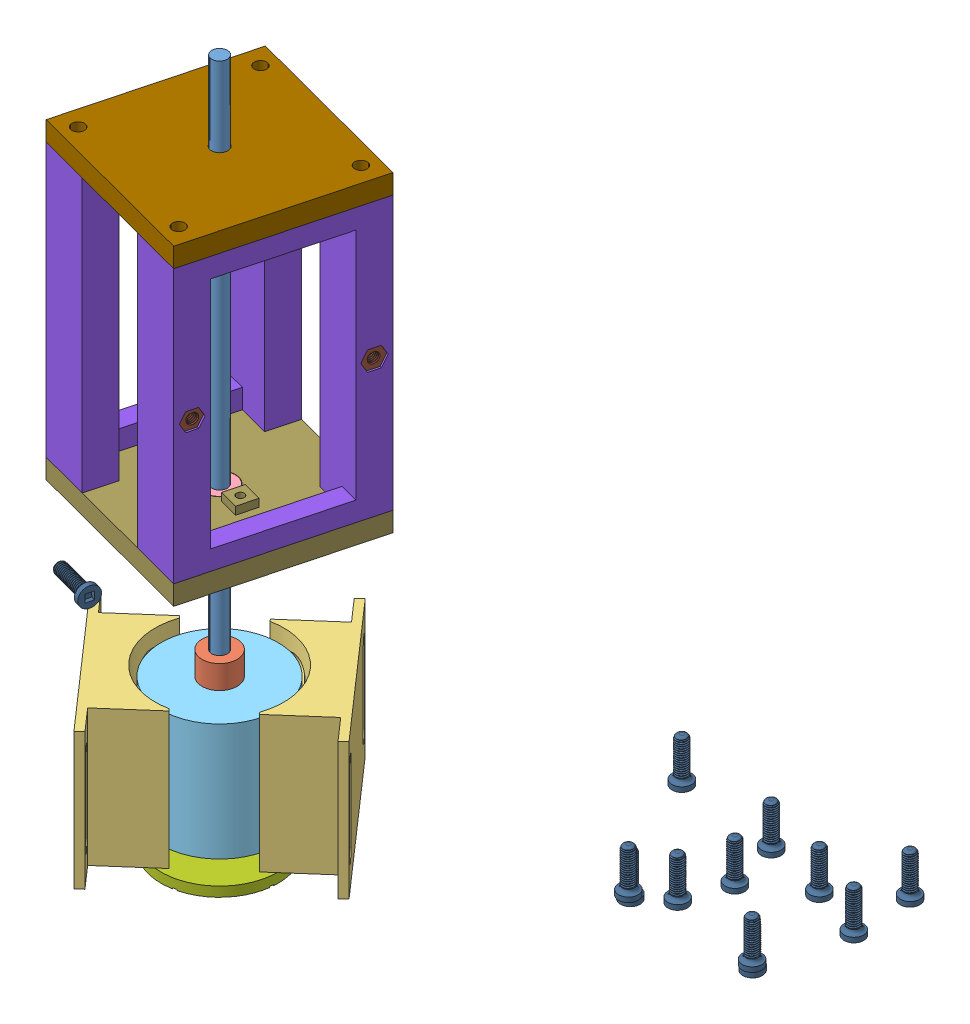
SolidWorks assembly motor 30mm diameter, configuration Default. Lengths in mm.
Overall size (286.31 208.16 173.67).
55 component instances, 12 part files, 103 mates.
Components (placement in the parent):
- 4mm diameter shaft 140mm long-1: 4mm diameter shaft 140mm long [Default] at (27.5327 12.6607 113.9865) size (4 140 4)
- collar-1: collar [Default] at (27.5327 14.5874 113.9865) x (0.999387 0 0.034997) z (-0.034997 0 0.999387) size (9 6 9.52)
- magnet_holder-1: magnet_holder [Default] at (57.6023 -0.4126 87.6082) x (0 1 0) z (0.659458 0 0.751741) size (35 16.75 45)
- collar-2: collar [Default] at (27.5327 -21.4126 113.9865) size (9 6 9.52)
- magnet_holder-2: magnet_holder [Default] at (-2.537 -0.4126 140.3648) x (0 1 0) z (-0.659458 0 -0.751741) size (35 16.75 45)
- shitty 4mm bearing-1: shitty 4mm bearing [Default] at (27.5327 130.3635 113.9865) x (-0.401704 0 -0.915769) z (-0.915769 0 0.401704) size (8 3 8)
- shitty 4mm bearing-2: shitty 4mm bearing [Default] at (27.5327 57.3635 113.9865) x (-0.401704 0 -0.915769) z (-0.915769 0 0.401704) size (8 3 8)
- rotor-like cylinder-1: rotor-like cylinder [Default] at (27.5327 -15.4126 113.9865) x (0.183673 0 0.982987) z (-0.982987 0 0.183673) size (30 30 30)
- 6.4mm magnet-1: 6.4mm magnet [Default] at (15.129 -0.4126 124.8676) x (0.659458 0 0.751741) z (-0.751741 0 0.659458) size (6.4 6.4 6.4)
- 6.4mm magnet-2: 6.4mm magnet [Default] at (22.8511 -10.4126 131.3958) x (0.659458 0 0.751741) z (-0.751741 0 0.659458) size (6.4 6.4 6.4)
- 6.4mm magnet-3: 6.4mm magnet [Default] at (9.662 9.5874 116.361) x (0.659458 0 0.751741) z (-0.751741 0 0.659458) size (6.4 6.4 6.4)
- 6.4mm magnet-4: 6.4mm magnet [Default] at (15.129 9.5874 124.8676) x (0.659458 0 0.751741) z (-0.751741 0 0.659458) size (6.4 6.4 6.4)
- 6.4mm magnet-5: 6.4mm magnet [Default] at (22.8511 9.5874 131.3958) x (0.659458 0 0.751741) z (-0.751741 0 0.659458) size (6.4 6.4 6.4)
- 6.4mm magnet-6: 6.4mm magnet [Default] at (22.8511 -0.4126 131.3958) x (0.659458 0 0.751741) z (-0.751741 0 0.659458) size (6.4 6.4 6.4)
- 6.4mm magnet-7: 6.4mm magnet [Default] at (15.129 -10.4126 124.8676) x (0.659458 0 0.751741) z (-0.751741 0 0.659458) size (6.4 6.4 6.4)
- 6.4mm magnet-8: 6.4mm magnet [Default] at (50.2145 9.5874 107.3915) x (0.659458 0 0.751741) z (-0.751741 0 0.659458) size (6.4 6.4 6.4)
- 6.4mm magnet-9: 6.4mm magnet [Default] at (50.2145 -0.4126 107.3915) x (0.659458 0 0.751741) z (-0.751741 0 0.659458) size (6.4 6.4 6.4)
- 6.4mm magnet-10: 6.4mm magnet [Default] at (9.662 -0.4126 116.361) x (0.659458 0 0.751741) z (-0.751741 0 0.659458) size (6.4 6.4 6.4)
- 6.4mm magnet-11: 6.4mm magnet [Default] at (44.7476 -0.4126 98.8849) x (0.659458 0 0.751741) z (-0.751741 0 0.659458) size (6.4 6.4 6.4)
- 6.4mm magnet-12: 6.4mm magnet [Default] at (44.7476 9.5874 98.8849) x (0.659458 0 0.751741) z (-0.751741 0 0.659458) size (6.4 6.4 6.4)
- 6.4mm magnet-13: 6.4mm magnet [Default] at (9.662 -10.4126 116.361) x (0.659458 0 0.751741) z (-0.751741 0 0.659458) size (6.4 6.4 6.4)
- 6.4mm magnet-14: 6.4mm magnet [Default] at (37.0254 -10.4126 92.3567) x (0.659458 0 0.751741) z (-0.751741 0 0.659458) size (6.4 6.4 6.4)
- 6.4mm magnet-15: 6.4mm magnet [Default] at (37.0254 -0.4126 92.3567) x (0.659458 0 0.751741) z (-0.751741 0 0.659458) size (6.4 6.4 6.4)
- 6.4mm magnet-16: 6.4mm magnet [Default] at (37.0254 9.5874 92.3567) x (0.659458 0 0.751741) z (-0.751741 0 0.659458) size (6.4 6.4 6.4)
- 6.4mm magnet-17: 6.4mm magnet [Default] at (44.7476 -10.4126 98.8849) x (0.659458 0 0.751741) z (-0.751741 0 0.659458) size (6.4 6.4 6.4)
- 6.4mm magnet-18: 6.4mm magnet [Default] at (50.2145 -10.4126 107.3915) x (0.659458 0 0.751741) z (-0.751741 0 0.659458) size (6.4 6.4 6.4)
- commutator-1: commutator [Default] at (27.5327 -23.9126 113.9865) x (0.977946 0 -0.20886) z (0.20886 0 0.977946) size (30 2.5 30)
- side-1: side [Default] at (44.9352 92.3635 118.5859) x (0 -1 0) z (-0.255519 0 0.966804) size (70 13 46)
- side-2: side [Default] at (10.1302 92.3635 109.3872) x (0 1 0) z (-0.255519 0 0.966804) size (70 13 46)
- top plate-1: top plate [Default] at (27.5327 127.3635 113.9865) x (0.966804 0 0.255519) z (-0.255519 0 0.966804) size (46 5 46)
- m3 10mm screw-1: m3 10mm screw [Default] at (40.4259 62.9575 161.0858) x (-0.006958 0.999629 0.026326) z (-0.255424 -0.02723 0.966446) size (5 11.25 5)
- threaded insert m3-1: threaded insert m3 [Default] at (49.9428 57.8635 100.1277) x (0.966804 0 0.255519) z (-0.255519 0 0.966804) size (5.77 8.2 5)
- bottom plate-1: bottom plate [Default] at (27.5327 57.3635 113.9865) x (-0.966804 0 -0.255519) z (-0.255519 0 0.966804) size (46 7 46)
- threaded insert m3-2: threaded insert m3 [Default] at (14.8962 126.8635 90.8651) x (-0.966804 0 -0.255519) z (-0.255519 0 0.966804) size (5.77 8.2 5)
- m3 10mm screw-2: m3 10mm screw [Default] at (257.6758 112.3701 207.42) size (5 11.25 5)
- threaded insert m3-3: threaded insert m3 [Default] at (5.1226 126.8635 127.8454) x (-0.966804 0 -0.255519) z (-0.255519 0 0.966804) size (5.77 8.2 5)
- m3 10mm screw-3: m3 10mm screw [Default] at (271.6653 150.9954 240.6279) size (5 11.25 5)
- threaded insert m3-4: threaded insert m3 [Default] at (40.1692 118.8635 137.1079) x (0.966804 0 0.255519) z (-0.255519 0 0.966804) size (5.77 8.2 5)
- m3 10mm screw-4: m3 10mm screw [Default] at (275.8721 126.0941 185.2162) size (5 11.25 5)
- threaded insert m3-5: threaded insert m3 [Default] at (0.9642 92.5248 126.4574) x (0.127759 -0.866025 -0.483402) z (-0.221286 -0.5 0.837277) size (5.77 8.2 5)
- m3 10mm screw-5: m3 10mm screw [Default] at (266.8499 122.8272 216.7168) size (5 11.25 5)
- threaded insert m3-6: threaded insert m3 [Default] at (10.6664 92.3635 89.7472) x (0.127759 -0.866025 -0.483402) z (-0.221286 -0.5 0.837277) size (5.77 8.2 5)
- m3 10mm screw-6: m3 10mm screw [Default] at (277.7139 156.6598 222.6465) size (5 11.25 5)
- threaded insert m3-7: threaded insert m3 [Default] at (40.1692 57.8635 137.1079) x (0.966804 0 0.255519) z (-0.255519 0 0.966804) size (5.77 8.2 5)
- m3 10mm screw-7: m3 10mm screw [Default] at (271.2692 134.1604 203.8679) size (5 11.25 5)
- threaded insert m3-8: threaded insert m3 [Default] at (46.4381 92.3635 99.2014) x (0.127759 -0.866025 -0.483402) z (-0.221286 -0.5 0.837277) size (5.77 8.2 5)
- m3 10mm screw-8: m3 10mm screw [Default] at (273.3226 122.8159 197.0775) size (5 11.25 5)
- threaded insert m3-9: threaded insert m3 [Default] at (5.1226 57.8635 127.8454) x (0.966804 0 0.255519) z (-0.255519 0 0.966804) size (5.77 8.2 5)
- m3 10mm screw-9: m3 10mm screw [Default] at (266.4595 142.05 220.7177) size (5 11.25 5)
- threaded insert m3-10: threaded insert m3 [Default] at (14.8962 65.8635 90.8651) x (-0.966804 0 -0.255519) z (-0.255519 0 0.966804) size (5.77 8.2 5)
- m3 10mm screw-10: m3 10mm screw [Default] at (270.1636 157.5042 251.7523) size (5 11.25 5)
- threaded insert m3-11: threaded insert m3 [Default] at (49.9428 126.8635 100.1277) x (-0.966804 0 -0.255519) z (-0.255519 0 0.966804) size (5.77 8.2 5)
- m3 10mm screw-11: m3 10mm screw [Default] at (269.274 174.2452 237.1528) size (5 11.25 5)
- threaded insert m3-12: threaded insert m3 [Default] at (36.7121 92.3635 136.0016) x (0.127759 -0.866025 -0.483402) z (-0.221286 -0.5 0.837277) size (5.77 8.2 5)
- m3 10mm screw-12: m3 10mm screw [Default] at (255.8389 142.0395 236.9166) size (5 11.25 5)
Mates (geometry in assembly coordinates):
- Concentric1: concentric aligned: circle of 4mm diameter shaft 140mm long-1; circle of rotor-like cylinder-1
- Concentric2: concentric aligned: circle of collar-1; circle of rotor-like cylinder-1
- Coincident6: coincident anti-aligned: plane of collar-1 through (27.5327 14.5874 113.9865) normal (0 -1 0); plane of rotor-like cylinder-1 through (27.5327 14.5874 113.9865) normal (0 1 0)
- Concentric4: concentric aligned: circle of 4mm diameter shaft 140mm long-1; circle of collar-2
- Coincident8: coincident anti-aligned: plane of collar-2 through (27.5327 -15.4126 113.9865) normal (0 1 0); plane of rotor-like cylinder-1 through (27.5327 -15.4126 113.9865) normal (0 -1 0)
- Concentric5: concentric anti-aligned: cylinder of magnet_holder-1 through (27.5327 -17.9126 113.9865) axis (0 1 0) radius 16.5; cylinder of rotor-like cylinder-1 through (27.5327 14.5874 113.9865) axis (0 -1 0) radius 15
- Concentric6: concentric anti-aligned: cylinder of magnet_holder-2 through (27.5327 -17.9126 113.9865) axis (0 1 0) radius 16.5; cylinder of rotor-like cylinder-1 through (27.5327 14.5874 113.9865) axis (0 -1 0) radius 15
- Parallel1: parallel aligned: plane of magnet_holder-1 through (7.3549 -17.9126 151.641) normal (0.659458 0 0.751741); plane of magnet_holder-2 through (67.4942 -17.9126 98.8843) normal (0.659458 0 0.751741)
- Coincident11: coincident aligned: plane of magnet_holder-1 through (7.3549 17.0874 151.641) normal (0 1 0); plane of magnet_holder-2 through (47.7105 17.0874 76.3321) normal (0 1 0)
- Concentric7: concentric anti-aligned: circle of magnet_holder-2; circle of 6.4mm magnet-5
- Coincident14: coincident anti-aligned: plane of magnet_holder-2 through (18.04 9.5874 135.6163) normal (0.751741 0 -0.659458); plane of 6.4mm magnet-5 through (18.04 9.5874 135.6163) normal (-0.751741 0 0.659458)
- Concentric8: concentric anti-aligned: circle of magnet_holder-2; circle of 6.4mm magnet-4
- Coincident16: coincident anti-aligned: plane of magnet_holder-2 through (10.3178 9.5874 129.0881) normal (0.751741 0 -0.659458); plane of 6.4mm magnet-4 through (10.3178 9.5874 129.0881) normal (-0.751741 0 0.659458)
- Concentric9: concentric anti-aligned: circle of magnet_holder-2; circle of 6.4mm magnet-3
- Coincident18: coincident anti-aligned: plane of magnet_holder-2 through (4.8508 9.5874 120.5815) normal (0.751741 0 -0.659458); plane of 6.4mm magnet-3 through (4.8508 9.5874 120.5815) normal (-0.751741 0 0.659458)
- Concentric10: concentric anti-aligned: circle of magnet_holder-2; circle of 6.4mm magnet-6
- Coincident19: coincident anti-aligned: plane of magnet_holder-2 through (18.04 -0.4126 135.6163) normal (0.751741 0 -0.659458); plane of 6.4mm magnet-6 through (18.04 -0.4126 135.6163) normal (-0.751741 0 0.659458)
- Concentric11: concentric anti-aligned: circle of magnet_holder-2; circle of 6.4mm magnet-2
- Coincident21: coincident anti-aligned: plane of magnet_holder-2 through (18.04 -10.4126 135.6163) normal (0.751741 0 -0.659458); plane of 6.4mm magnet-2 through (18.04 -10.4126 135.6163) normal (-0.751741 0 0.659458)
- Concentric12: concentric anti-aligned: circle of magnet_holder-2; circle of 6.4mm magnet-1
- Coincident23: coincident anti-aligned: plane of magnet_holder-2 through (10.3178 -0.4126 129.0881) normal (0.751741 0 -0.659458); plane of 6.4mm magnet-1 through (10.3178 -0.4126 129.0881) normal (-0.751741 0 0.659458)
- Concentric13: concentric anti-aligned: circle of magnet_holder-2; circle of 6.4mm magnet-7
- Coincident25: coincident anti-aligned: plane of magnet_holder-2 through (10.3178 -10.4126 129.0881) normal (0.751741 0 -0.659458); plane of 6.4mm magnet-7 through (10.3178 -10.4126 129.0881) normal (-0.751741 0 0.659458)
- Concentric14: concentric anti-aligned: circle of magnet_holder-2; circle of 6.4mm magnet-13
- Coincident27: coincident anti-aligned: plane of magnet_holder-2 through (4.8508 -10.4126 120.5815) normal (0.751741 0 -0.659458); plane of 6.4mm magnet-13 through (4.8508 -10.4126 120.5815) normal (-0.751741 0 0.659458)
- Concentric15: concentric anti-aligned: circle of magnet_holder-2; circle of 6.4mm magnet-10
- Coincident28: coincident anti-aligned: plane of magnet_holder-2 through (4.8508 -0.4126 120.5815) normal (0.751741 0 -0.659458); plane of 6.4mm magnet-10 through (4.8508 -0.4126 120.5815) normal (-0.751741 0 0.659458)
- Concentric16: concentric aligned: circle of magnet_holder-1; circle of 6.4mm magnet-8
- Concentric21: concentric aligned: circle of magnet_holder-1; circle of 6.4mm magnet-9
- Concentric22: concentric aligned: circle of magnet_holder-1; circle of 6.4mm magnet-18
- Concentric23: concentric aligned: circle of magnet_holder-1; circle of 6.4mm magnet-12
- Concentric24: concentric aligned: circle of magnet_holder-1; circle of 6.4mm magnet-11
- Concentric25: concentric aligned: circle of magnet_holder-1; circle of 6.4mm magnet-17
- Concentric26: concentric aligned: circle of magnet_holder-1; circle of 6.4mm magnet-14
- Concentric27: concentric aligned: circle of magnet_holder-1; circle of 6.4mm magnet-15
- Concentric28: concentric aligned: circle of magnet_holder-1; circle of 6.4mm magnet-16
- Coincident39: coincident anti-aligned: plane of magnet_holder-1 through (50.2145 9.5874 107.3915) normal (-0.751741 0 0.659458); plane of 6.4mm magnet-8 through (50.2145 9.5874 107.3915) normal (0.751741 0 -0.659458)
- Coincident40: coincident anti-aligned: plane of magnet_holder-1 through (44.7476 9.5874 98.8849) normal (-0.751741 0 0.659458); plane of 6.4mm magnet-12 through (44.7476 9.5874 98.8849) normal (0.751741 0 -0.659458)
- Coincident41: coincident anti-aligned: plane of magnet_holder-1 through (37.0254 9.5874 92.3567) normal (-0.751741 0 0.659458); plane of 6.4mm magnet-16 through (37.0254 9.5874 92.3567) normal (0.751741 0 -0.659458)
- Coincident42: coincident anti-aligned: plane of magnet_holder-1 through (37.0254 -0.4126 92.3567) normal (-0.751741 0 0.659458); plane of 6.4mm magnet-15 through (37.0254 -0.4126 92.3567) normal (0.751741 0 -0.659458)
- Coincident43: coincident anti-aligned: plane of magnet_holder-1 through (44.7476 -0.4126 98.8849) normal (-0.751741 0 0.659458); plane of 6.4mm magnet-11 through (44.7476 -0.4126 98.8849) normal (0.751741 0 -0.659458)
- Coincident44: coincident anti-aligned: plane of magnet_holder-1 through (50.2145 -0.4126 107.3915) normal (-0.751741 0 0.659458); plane of 6.4mm magnet-9 through (50.2145 -0.4126 107.3915) normal (0.751741 0 -0.659458)
- Coincident45: coincident anti-aligned: plane of magnet_holder-1 through (50.2145 -10.4126 107.3915) normal (-0.751741 0 0.659458); plane of 6.4mm magnet-18 through (50.2145 -10.4126 107.3915) normal (0.751741 0 -0.659458)
- Coincident46: coincident anti-aligned: plane of magnet_holder-1 through (44.7476 -10.4126 98.8849) normal (-0.751741 0 0.659458); plane of 6.4mm magnet-17 through (44.7476 -10.4126 98.8849) normal (0.751741 0 -0.659458)
- Coincident47: coincident anti-aligned: plane of magnet_holder-1 through (37.0254 -10.4126 92.3567) normal (-0.751741 0 0.659458); plane of 6.4mm magnet-14 through (37.0254 -10.4126 92.3567) normal (0.751741 0 -0.659458)
- Distance1: distance = 2.5 mm aligned: plane of magnet_holder-2 through (47.7105 -17.9126 76.3321) normal (0 -1 0); plane of rotor-like cylinder-1 through (27.5327 -15.4126 113.9865) normal (0 -1 0)
- Concentric29: concentric anti-aligned: circle of collar-2; cylinder of commutator-1 through (27.5327 -21.4126 113.9865) axis (0 -1 0) radius 2
- Coincident49: coincident anti-aligned: plane of collar-2 through (27.5327 -21.4126 113.9865) normal (0 -1 0); plane of commutator-1 through (27.5327 -21.4126 113.9865) normal (0 1 0)
- Coincident51: coincident anti-aligned: plane of side-1 through (44.9352 118.8635 118.5859) normal (0 1 0); plane of threaded insert m3-4 through (40.1692 118.8635 137.1079) normal (0 -1 0)
- Coincident52: coincident aligned: line of side-1 through (38.135 118.8635 139.1561) axis (0.966804 0 0.255519); line of threaded insert m3-4 through (38.135 118.8635 139.1561) axis (0.966804 0 0.255519)
- Coincident53: coincident aligned: line of side-1 through (37.3783 118.8635 136.3703) axis (0.262116 0 0.965036); line of threaded insert m3-4 through (37.3783 118.8635 136.3703) axis (0.262116 0 0.965036)
- Coincident54: coincident anti-aligned: plane of side-1 through (44.9352 118.8635 118.5859) normal (0 1 0); plane of threaded insert m3-11 through (49.9428 118.8635 100.1277) normal (0 -1 0)
- Coincident55: coincident anti-aligned: line of side-1 through (49.1861 118.8635 97.3418) axis (-0.704688 0 0.709518); line of threaded insert m3-11 through (47.1519 118.8635 99.39) axis (0.704688 0 -0.709518)
- Coincident56: coincident anti-aligned: line of side-1 through (50.6995 118.8635 102.9135) axis (0.704688 0 -0.709518); line of threaded insert m3-11 through (52.7337 118.8635 100.8653) axis (-0.704688 0 0.709518)
- Coincident57: coincident anti-aligned: line of side-1 through (47.9085 118.8635 102.1759) axis (0.966804 0 0.255519); line of threaded insert m3-11 through (50.6995 118.8635 102.9135) axis (-0.966804 0 -0.255519)
- Coincident65: coincident anti-aligned: plane of side-1 through (41.5513 92.3635 117.6915) normal (0.966804 0 0.255519); plane of threaded insert m3-8 through (46.4381 92.3635 99.2014) normal (-0.966804 0 -0.255519)
- Coincident66: coincident aligned: line of side-1 through (46.0693 94.8635 100.5969) axis (-0.127759 -0.866025 0.483402); line of threaded insert m3-8 through (46.0693 94.8635 100.5969) axis (-0.127759 -0.866025 0.483402)
- Coincident67: coincident aligned: line of side-1 through (45.7005 92.3635 101.9923) axis (0.127759 -0.866025 -0.483402); line of threaded insert m3-8 through (45.7005 92.3635 101.9923) axis (0.127759 -0.866025 -0.483402)
- Coincident68: coincident anti-aligned: plane of side-1 through (41.5513 92.3635 117.6915) normal (0.966804 0 0.255519); plane of threaded insert m3-12 through (36.7121 92.3635 136.0016) normal (-0.966804 0 -0.255519)
- Coincident69: coincident aligned: line of side-1 through (36.3195 94.7022 137.4871) axis (-0.127759 -0.866025 0.483402); line of threaded insert m3-12 through (36.3433 94.8635 137.3971) axis (-0.127759 -0.866025 0.483402)
- Coincident70: coincident aligned: line of side-1 through (35.9745 92.3635 138.7925) axis (0.127759 -0.866025 -0.483402); line of threaded insert m3-12 through (35.9745 92.3635 138.7925) axis (0.127759 -0.866025 -0.483402)
- Coincident71: coincident anti-aligned: plane of side-1 through (44.9352 65.8635 118.5859) normal (0 -1 0); plane of threaded insert m3-7 through (40.1692 65.8635 137.1079) normal (0 1 0)
- Coincident72: coincident anti-aligned: line of side-1 through (39.4125 65.8635 134.3221) axis (0.966804 0 0.255519); line of threaded insert m3-7 through (42.2035 65.8635 135.0597) axis (-0.966804 0 -0.255519)
- Coincident73: coincident anti-aligned: line of side-1 through (38.135 65.8635 139.1561) axis (-0.262116 0 -0.965036); line of threaded insert m3-7 through (37.3783 65.8635 136.3703) axis (0.262116 0 0.965036)
- Coincident74: coincident anti-aligned: plane of side-1 through (44.9352 65.8635 118.5859) normal (0 -1 0); plane of threaded insert m3-1 through (49.9428 65.8635 100.1277) normal (0 1 0)
- Coincident75: coincident: plane of side-1 through (51.9771 65.8635 98.0795) normal (-0.965036 0 0.262116); line of threaded insert m3-1 through (52.7337 65.8635 100.8653) axis (-0.262116 0 -0.965036)
- Coincident76: coincident anti-aligned: plane of side-1 through (52.7337 65.8635 100.8653) normal (-0.709518 0 -0.704688); plane of threaded insert m3-1 through (50.6995 65.8635 102.9135) normal (0.709518 0 0.704688)
- Coincident77: coincident anti-aligned: plane of side-2 through (10.1302 118.8635 109.3872) normal (0 1 0); plane of threaded insert m3-3 through (5.1226 118.8635 127.8454) normal (0 -1 0)
- Coincident78: coincident anti-aligned: plane of side-2 through (7.1568 118.8635 125.7972) normal (-0.255519 0 0.966804); plane of threaded insert m3-3 through (4.3659 118.8635 125.0595) normal (0.255519 0 -0.966804)
- Coincident79: coincident: plane of side-2 through (7.9135 118.8635 128.583) normal (-0.965036 0 0.262116); line of threaded insert m3-3 through (7.1568 126.8635 125.7972) axis (0.262116 0 0.965036)
- Coincident80: coincident anti-aligned: plane of side-2 through (10.1302 118.8635 109.3872) normal (0 1 0); plane of threaded insert m3-2 through (14.8962 118.8635 90.8651) normal (0 -1 0)
- Coincident81: coincident anti-aligned: plane of side-2 through (16.9304 118.8635 88.8169) normal (-0.255519 0 0.966804); plane of threaded insert m3-2 through (14.1395 118.8635 88.0793) normal (0.255519 0 -0.966804)
- Coincident82: coincident: plane of side-2 through (17.6871 118.8635 91.6027) normal (-0.965036 0 0.262116); line of threaded insert m3-2 through (16.9304 126.8635 88.8169) axis (0.262116 0 0.965036)
- Coincident84: coincident anti-aligned: plane of side-2 through (13.514 92.3635 110.2815) normal (-0.966804 0 -0.255519); plane of threaded insert m3-6 through (18.4008 92.3635 91.7914) normal (0.966804 0 0.255519)
- Coincident85: coincident anti-aligned: plane of side-2 through (18.7696 89.8635 90.3959) normal (0 1 0); plane of threaded insert m3-6 through (18.032 89.8635 93.1868) normal (0 -1 0)
- Coincident86: coincident anti-aligned: plane of side-2 through (19.1384 92.3635 89.0004) normal (-0.221286 0.5 0.837277); plane of threaded insert m3-6 through (18.7696 89.8635 90.3959) normal (0.221286 -0.5 -0.837277)
- Coincident88: coincident anti-aligned: plane of side-2 through (13.514 92.3635 110.2815) normal (-0.966804 0 -0.255519); plane of threaded insert m3-5 through (8.6986 92.5248 128.5015) normal (0.966804 0 0.255519)
- Coincident89: coincident anti-aligned: plane of side-2 through (7.9372 92.3635 131.3825) normal (0.221286 -0.5 -0.837277); plane of threaded insert m3-5 through (8.3298 95.0248 129.897) normal (-0.221286 0.5 0.837277)
- Parallel9: parallel anti-aligned: plane of side-2 through (9.3173 92.3635 126.1608) normal (-0.221286 0.5 0.837277); plane of threaded insert m3-5 through (9.0674 90.0248 127.1061) normal (0.221286 -0.5 -0.837277)
- Coincident91: coincident anti-aligned: plane of side-2 through (8.9722 90.0248 127.4662) normal (0 1 0); plane of threaded insert m3-5 through (8.3298 90.0248 129.897) normal (0 -1 0)
- Coincident92: coincident anti-aligned: plane of side-2 through (10.1302 65.8635 109.3872) normal (0 -1 0); plane of threaded insert m3-9 through (5.1226 65.8635 127.8454) normal (0 1 0)
- Coincident93: coincident anti-aligned: plane of side-2 through (4.3659 65.8635 125.0595) normal (-0.255519 0 0.966804); plane of threaded insert m3-9 through (7.1568 65.8635 125.7972) normal (0.255519 0 -0.966804)
- Coincident94: coincident anti-aligned: plane of side-2 through (2.3316 65.8635 127.1077) normal (0.709518 0 0.704688); plane of threaded insert m3-9 through (4.3659 65.8635 125.0595) normal (-0.709518 0 -0.704688)
- Coincident95: coincident anti-aligned: plane of side-2 through (10.1302 65.8635 109.3872) normal (0 -1 0); plane of threaded insert m3-10 through (14.8962 65.8635 90.8651) normal (0 1 0)
- Coincident96: coincident anti-aligned: plane of side-2 through (12.8619 65.8635 92.9133) normal (0.965036 0 -0.262116); plane of threaded insert m3-10 through (12.8619 57.8635 92.9133) normal (-0.965036 0 0.262116)
- Coincident97: coincident anti-aligned: plane of side-2 through (14.1395 65.8635 88.0793) normal (-0.255519 0 0.966804); plane of threaded insert m3-10 through (14.1395 57.8635 88.0793) normal (0.255519 0 -0.966804)
- Coincident98: coincident anti-aligned: plane of side-2 through (-0.5807 57.3635 130.3461) normal (0 -1 0); plane of bottom plate-1 through (27.5327 57.3635 113.9865) normal (0 1 0)
- Coincident99: coincident aligned: plane of side-2 through (11.1731 57.3635 85.8731) normal (0.255519 0 -0.966804); plane of bottom plate-1 through (55.6461 52.3635 97.627) normal (0.255519 0 -0.966804)
- Coincident100: coincident aligned: plane of side-2 through (5.2962 92.3635 108.1096) normal (-0.966804 0 -0.255519); plane of bottom plate-1 through (11.1731 52.3635 85.8731) normal (-0.966804 0 -0.255519)
- Coincident101: coincident aligned: plane of side-1 through (49.7692 92.3635 119.8634) normal (0.966804 0 0.255519); plane of bottom plate-1 through (55.6461 52.3635 97.627) normal (0.966804 0 0.255519)
- Coincident102: coincident anti-aligned: plane of side-1 through (43.8922 57.3635 142.0999) normal (0 -1 0); plane of bottom plate-1 through (27.5327 57.3635 113.9865) normal (0 1 0)
- Coincident103: coincident aligned: plane of side-1 through (55.6461 127.3635 97.627) normal (0.255519 0 -0.966804); plane of bottom plate-1 through (55.6461 52.3635 97.627) normal (0.255519 0 -0.966804)
- Coincident104: coincident anti-aligned: plane of side-1 through (43.8922 127.3635 142.0999) normal (0 1 0); plane of top plate-1 through (27.5327 127.3635 113.9865) normal (0 -1 0)
- Coincident105: coincident aligned: plane of side-1 through (49.7692 92.3635 119.8634) normal (0.966804 0 0.255519); plane of top plate-1 through (43.8922 132.3635 142.0999) normal (0.966804 0 0.255519)
- Coincident106: coincident aligned: plane of side-1 through (55.6461 127.3635 97.627) normal (0.255519 0 -0.966804); plane of top plate-1 through (11.1731 132.3635 85.8731) normal (0.255519 0 -0.966804)
- Concentric30: concentric anti-aligned: circle of shitty 4mm bearing-2; circle of bottom plate-1
- Coincident107: coincident anti-aligned: plane of shitty 4mm bearing-2 through (27.5327 54.3635 113.9865) normal (0 -1 0); plane of bottom plate-1 through (27.5327 54.3635 113.9865) normal (0 1 0)
- Concentric31: concentric anti-aligned: circle of shitty 4mm bearing-1; circle of top plate-1
- Coincident108: coincident anti-aligned: plane of shitty 4mm bearing-1 through (27.5327 130.3635 113.9865) normal (0 1 0); plane of top plate-1 through (27.5327 130.3635 113.9865) normal (0 -1 0)
- Concentric32: concentric anti-aligned: circle of 4mm diameter shaft 140mm long-1; circle of bottom plate-1
- Parallel10: parallel aligned: plane of magnet_holder-1 through (44.8227 -0.4126 98.819) normal (-0.751741 0 0.659458); plane of magnet_holder-2 through (20.1817 -17.9126 143.5168) normal (-0.751741 0 0.659458)
- Coincident110: coincident anti-aligned: plane of side-1 through (41.5513 92.3635 117.6915) normal (0.966804 0 0.255519); plane of m3 10mm screw-1 through (30.7579 62.9575 158.5306) normal (-0.966804 0 -0.255519)
- Tangent5: tangent: plane of magnet_holder-2 through (20.1817 -17.9126 143.5168) normal (-0.751741 0 0.659458); torus of m3 10mm screw-1
